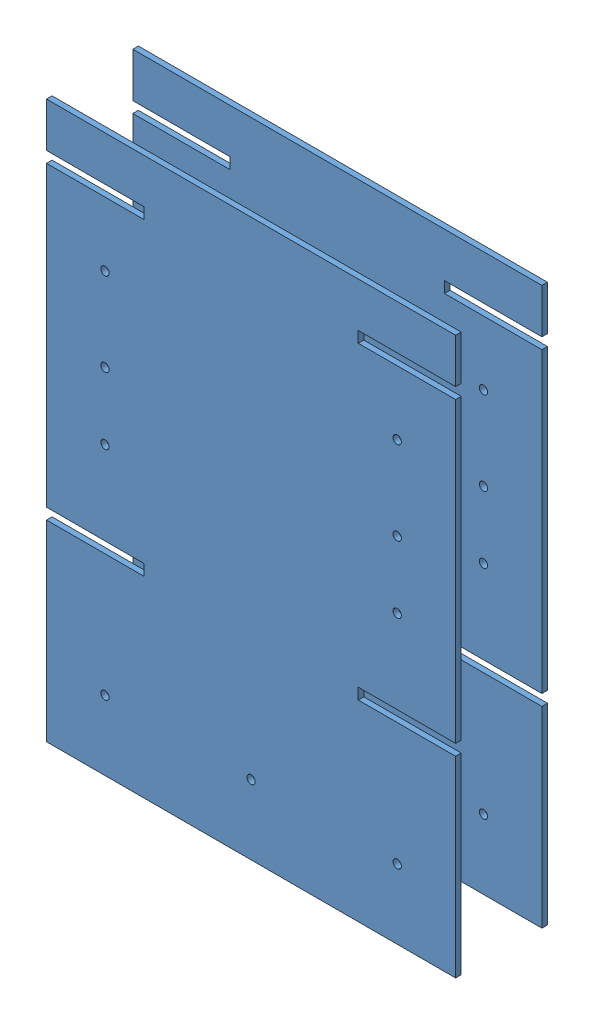
SolidWorks assembly chapa_montagem, configuration Valor predeterminado. Lengths in mm.
Overall size (147 200 36.45).
11 component instances, 2 part files, 12 mates.
Components (placement in the parent):
- chapa-1: chapa [Valor predeterminado] at (-18.1566 10.6922 199) size (147 200 2)
- countersunk slotted raised head screw_iso-1: countersunk slotted raised head screw_iso [ISO 2010 - M3 x 30 --- 30N] at (-70.6566 -64.3078 203.3736) x (0 0 -1) z (-0.244417 0.96967 0) size (30.69 5.5 5.44)
- countersunk slotted raised head screw_iso-2: countersunk slotted raised head screw_iso [ISO 2010 - M3 x 30 --- 30N] at (34.3434 -64.3078 204.0583) x (0 0 -1) z (-0.882458 0.470391 0) size (30.69 5.5 5.44)
- countersunk slotted raised head screw_iso-3: countersunk slotted raised head screw_iso [ISO 2010 - M3 x 30 --- 30N] at (34.3434 13.6922 204.2375) x (0 0 -1) z (0.649404 -0.760444 0) size (30.69 5.5 5.44)
- countersunk slotted raised head screw_iso-4: countersunk slotted raised head screw_iso [ISO 2010 - M3 x 30 --- 30N] at (34.3434 37.6922 203.655) x (0 0 -1) z (0.871892 0.489698 0) size (30.69 5.5 5.44)
- countersunk slotted raised head screw_iso-5: countersunk slotted raised head screw_iso [ISO 2010 - M3 x 30 --- 30N] at (34.3434 67.6922 203.8907) x (0 0 -1) z (0.898776 -0.438408 0) size (30.69 5.5 5.44)
- countersunk slotted raised head screw_iso-6: countersunk slotted raised head screw_iso [ISO 2010 - M3 x 30 --- 30N] at (-70.6566 67.6922 203.4844) x (0 0 -1) z (-0.167696 -0.985839 0) size (30.69 5.5 5.44)
- countersunk slotted raised head screw_iso-7: countersunk slotted raised head screw_iso [ISO 2010 - M3 x 30 --- 30N] at (-70.6566 37.6922 204.0291) x (0 0 -1) z (0.961696 -0.274118 0) size (30.69 5.5 5.44)
- countersunk slotted raised head screw_iso-8: countersunk slotted raised head screw_iso [ISO 2010 - M3 x 30 --- 30N] at (-70.6566 13.6922 203.5823) x (0 0 -1) z (-0.828055 0.560647 0) size (30.69 5.5 5.44)
- countersunk slotted raised head screw_iso-9: countersunk slotted raised head screw_iso [ISO 2010 - M3 x 30 --- 30N] at (-18.1566 -64.3078 204.4619) x (0 0 -1) z (-0.994832 0.101533 0) size (30.69 5.5 5.44)
- chapa-2: chapa [Valor predeterminado] at (-18.1566 10.6922 168) size (147 200 2)
Mates (geometry in assembly coordinates):
- Concêntrico2: concentric aligned: cylinder of chapa-1 through (-70.6566 -64.3078 199) axis (0 0 1) radius 1.5; cylinder of countersunk slotted raised head screw_iso-1 through (-70.6566 -64.3078 219.2486) axis (0 0 1) radius 1.5
- Concêntrico3: concentric aligned: cylinder of chapa-1 through (-70.6566 13.6922 199) axis (0 0 1) radius 1.5; cylinder of countersunk slotted raised head screw_iso-8 through (-70.6566 13.6922 219.4573) axis (0 0 1) radius 1.5
- Concêntrico4: concentric aligned: cylinder of chapa-1 through (-70.6566 37.6922 199) axis (0 0 1) radius 1.5; cylinder of countersunk slotted raised head screw_iso-7 through (-70.6566 37.6922 219.9041) axis (0 0 1) radius 1.5
- Concêntrico5: concentric aligned: circle of chapa-1; cylinder of countersunk slotted raised head screw_iso-6 through (-70.6566 67.6922 219.3594) axis (0 0 1) radius 1.5
- Concêntrico6: concentric aligned: cylinder of chapa-1 through (34.3434 67.6922 199) axis (0 0 1) radius 1.5; cylinder of countersunk slotted raised head screw_iso-5 through (34.3434 67.6922 219.7657) axis (0 0 1) radius 1.5
- Concêntrico7: concentric aligned: cylinder of chapa-1 through (34.3434 37.6922 199) axis (0 0 1) radius 1.5; cylinder of countersunk slotted raised head screw_iso-4 through (34.3434 37.6922 219.53) axis (0 0 1) radius 1.5
- Concêntrico8: concentric aligned: cylinder of chapa-1 through (34.3434 13.6922 199) axis (0 0 1) radius 1.5; cylinder of countersunk slotted raised head screw_iso-3 through (34.3434 13.6922 220.1125) axis (0 0 1) radius 1.5
- Concêntrico9: concentric aligned: circle of chapa-1; cylinder of countersunk slotted raised head screw_iso-2 through (34.3434 -64.3078 219.9333) axis (0 0 1) radius 1.5
- Concêntrico10: concentric aligned: cylinder of chapa-1 through (-18.1566 -64.3078 199) axis (0 0 1) radius 1.5; cylinder of countersunk slotted raised head screw_iso-9 through (-18.1566 -64.3078 220.3369) axis (0 0 1) radius 1.5
- Coincidente7: coincident aligned: plane of chapa-1 through (-91.6566 -16.3078 201) normal (-1 0 0); plane of chapa-2 through (-91.6566 -16.3078 170) normal (-1 0 0)
- Coincidente8: coincident aligned: plane of chapa-1 through (-81.6566 -89.3078 201) normal (0 -1 0); plane of chapa-2 through (-81.6566 -89.3078 170) normal (0 -1 0)
- Distância1: distance = 29 mm anti-aligned: plane of chapa-2 through (-81.6566 100.6922 170) normal (0 0 1); plane of chapa-1 through (-81.6566 100.6922 199) normal (0 0 -1)
